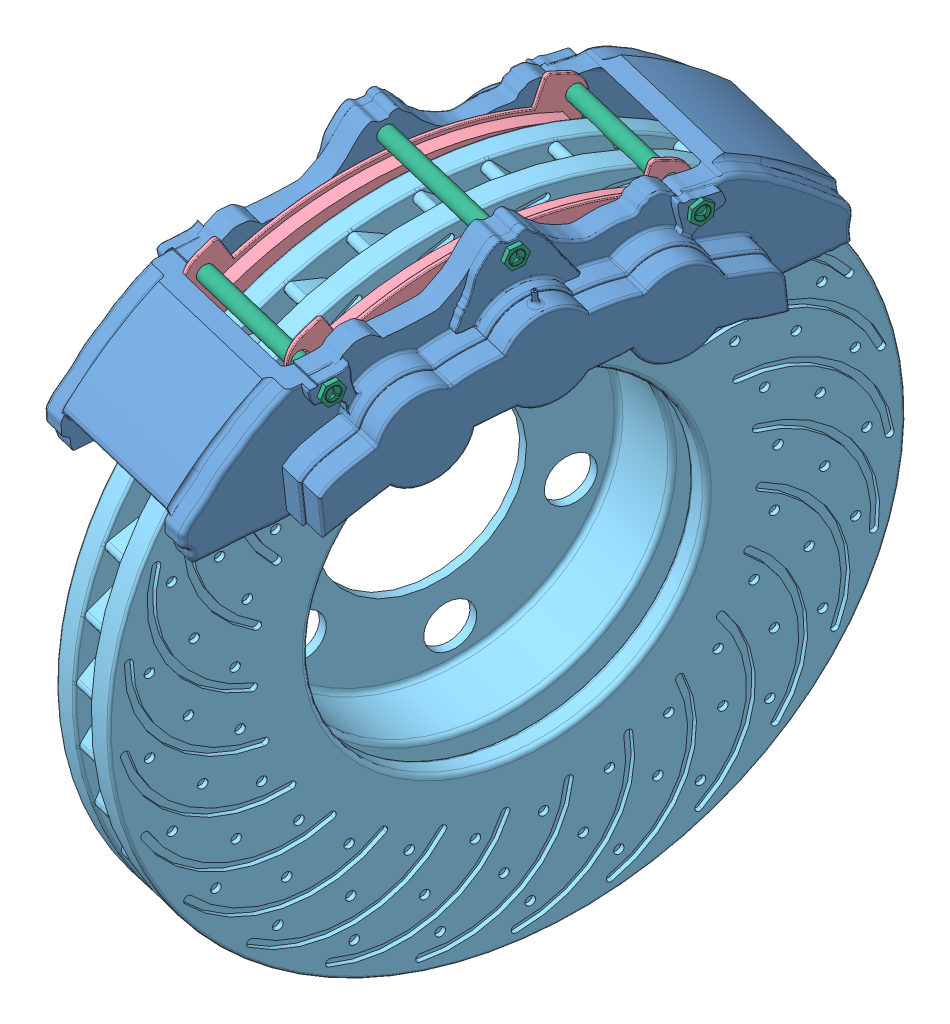
SolidWorks assembly Brake Assemble, configuration Default. Lengths in mm.
Overall size (85.72 212.78 212.98).
9 component instances, 6 part files, 19 mates.
Components (placement in the parent):
- Brake Caliper 1-1: Brake Caliper 1 [Default] at (-2.2395 31.9468 202.1188) x (0.977716 -0.038754 0.206322) z (-0.209533 -0.119701 0.970447) size (56.21 39.49 128.47)
- Brake piston (R)-1: Brake piston (R) [Default] at (36.2171 93.3172 217.992) x (0.208982 0.272999 -0.939041) z (0.019934 -0.961233 -0.275014) size (10 15 10)
- Piston rubber-1: Piston rubber [Default] at (45.9845 92.9301 220.0531) x (0.195813 0.52267 -0.829743) z (-0.075683 0.851654 0.518612) size (12.43 7.98 12.43)
- Brake Pad-1: Brake Pad [Default] at (8.2987 34.9481 206.059) x (0.977716 -0.038754 0.206322) z (0.048348 -0.914826 -0.400944) size (4.02 74.2 43.13)
- Brake Pad-2: Brake Pad [Default] at (34.2749 34.3435 211.2716) x (-0.977716 0.038754 -0.206322) z (-0.075256 -0.982195 0.172134) size (4.02 74.2 43.13)
- Rotor Brake -1: Rotor Brake  [Default] at (29.0837 32.7757 207.7171) x (-0.977716 0.038754 -0.206322) z (-0.110788 0.739558 0.663912) size (27 150 150)
- Sliding Pin-5: Sliding Pin [Default] at (51.7846 103.9726 187.4377) x (-0.977716 0.038754 -0.206322) z (-0.057387 -0.994718 0.085103) size (46.59 4.33 5)
- Sliding Pin-6: Sliding Pin [Default] at (44.7399 109.0172 221.7687) x (-0.977716 0.038754 -0.206322) z (0.092227 -0.803596 -0.587986) size (46.59 4.33 5)
- Sliding Pin-7: Sliding Pin [Default] at (37.1518 95.6132 255.2094) x (-0.977716 0.038754 -0.206322) z (0.092227 -0.803596 -0.587986) size (46.59 4.33 5)
Mates (geometry in assembly coordinates):
- Concentric3: concentric: cylinder of Brake Caliper 1-1 through (50.8829 92.7359 221.0868) axis (-0.977716 0.038754 -0.206322) radius 6.25; cylinder of Brake piston (R)-1 through (36.2171 93.3172 217.992) axis (-0.977716 0.038754 -0.206322) radius 4.5
- Concentric4: concentric: cylinder of Brake piston (R)-1 through (36.2171 93.3172 217.992) axis (-0.977716 0.038754 -0.206322) radius 4.5; cylinder of Piston rubber-1 through (38.1823 93.2393 218.4067) axis (0.977716 -0.038754 0.206322) radius 4.515
- Width1: width: plane of Brake piston (R)-1 through (44.9494 91.5647 224.7504) normal (-0.977716 0.038754 -0.206322); plane of Brake piston (R)-1 through (37.2321 92.0112 222.6303) normal (0.977716 -0.038754 0.206322); plane of Piston rubber-1 through (45.9845 92.9301 220.0531) normal (0.977716 -0.038754 0.206322); plane of Piston rubber-1 through (38.1823 93.2393 218.4067) normal (-0.977716 0.038754 -0.206322)
- Coincident4: coincident: plane of Brake piston (R)-1 through (35.1722 91.9522 222.6872) normal (-0.977716 0.038754 -0.206322); plane of Brake Pad-2 through (35.3498 35.8371 211.3052) normal (0.977716 -0.038754 0.206322)
- Width2: width: plane of Rotor Brake -1 through (14.4179 33.357 204.6223) normal (-0.977716 0.038754 -0.206322); plane of Rotor Brake -1 through (29.0837 32.7757 207.7171) normal (0.977716 -0.038754 0.206322); plane of Brake Pad-1 through (11.2318 34.8318 206.6779) normal (0.977716 -0.038754 0.206322); plane of Brake Pad-2 through (31.3418 34.4598 210.6526) normal (-0.977716 0.038754 -0.206322)
- Width3: width: plane of Brake Pad-1 through (11.2318 34.8318 206.6779) normal (0.977716 -0.038754 0.206322); plane of Brake Pad-2 through (31.3418 34.4598 210.6526) normal (-0.977716 0.038754 -0.206322); plane of Rotor Brake -1 through (29.0837 32.7757 207.7171) normal (0.977716 -0.038754 0.206322); plane of Rotor Brake -1 through (14.4179 33.357 204.6223) normal (-0.977716 0.038754 -0.206322)
- Distance5: distance = 3 mm: cylinder of Rotor Brake -1 through (4.6408 33.7445 202.5591) axis (0.977716 -0.038754 0.206322) radius 40; cylinder of Brake Pad-1 through (7.321 34.9869 205.8527) axis (0.977716 -0.038754 0.206322) radius 46.5
- Distance6: distance = 3 mm: cylinder of Brake Pad-2 through (35.2526 34.3048 211.4779) axis (-0.977716 0.038754 -0.206322) radius 46.5; cylinder of Rotor Brake -1 through (4.6408 33.7445 202.5591) axis (0.977716 -0.038754 0.206322) radius 40
- Coincident8: coincident: plane of Brake Caliper 1-1 through (20.3318 98.0959 156.051) normal (0.977716 -0.038754 0.206322); plane of Brake Pad-1 through (7.2661 36.4363 206.385) normal (-0.977716 0.038754 -0.206322)
- Concentric5: concentric: cylinder of Brake Caliper 1-1 through (60.3482 103.6332 189.2449) axis (-0.977716 0.038754 -0.206322) radius 1.75; cylinder of Sliding Pin-5 through (7.7874 105.7166 178.1532) axis (0.977716 -0.038754 0.206322) radius 1.75
- Coincident9: coincident: plane of Brake Caliper 1-1 through (52.1533 106.232 186.115) normal (0.977716 -0.038754 0.206322); plane of Sliding Pin-5 through (51.7846 103.9726 187.4377) normal (-0.977716 0.038754 -0.206322)
- Concentric6: concentric: cylinder of Brake Caliper 1-1 through (53.3035 108.6778 223.5758) axis (-0.977716 0.038754 -0.206322) radius 1.75; cylinder of Sliding Pin-6 through (0.7427 110.7611 212.4842) axis (0.977716 -0.038754 0.206322) radius 1.75
- Coincident10: coincident: plane of Brake Caliper 1-1 through (42.8419 103.6191 229.749) normal (0.977716 -0.038754 0.206322); plane of Sliding Pin-6 through (44.7399 109.0172 221.7687) normal (-0.977716 0.038754 -0.206322)
- Concentric7: concentric: cylinder of Brake Pad-2 through (33.6933 104.6897 183.62) axis (0.977716 -0.038754 0.206322) radius 1.75; cylinder of Sliding Pin-5 through (7.7874 105.7166 178.1532) axis (0.977716 -0.038754 0.206322) radius 1.75
- Concentric8: concentric: cylinder of Brake Pad-1 through (25.3863 105.019 181.867) axis (-0.977716 0.038754 -0.206322) radius 1.75; cylinder of Sliding Pin-5 through (7.7874 105.7166 178.1532) axis (0.977716 -0.038754 0.206322) radius 1.75
- Concentric9: concentric: cylinder of Brake Pad-1 through (10.7535 96.6596 249.6388) axis (-0.977716 0.038754 -0.206322) radius 1.75; cylinder of Sliding Pin-7 through (-6.8454 97.3572 245.925) axis (0.977716 -0.038754 0.206322) radius 1.75
- Coincident11: coincident: plane of Brake Caliper 1-1 through (36.5677 97.6867 258.3669) normal (0.977716 -0.038754 0.206322); plane of Sliding Pin-7 through (37.1518 95.6132 255.2094) normal (-0.977716 0.038754 -0.206322)
- Concentric10: concentric: cylinder of Brake Caliper 1-1 through (45.7154 95.2738 257.0166) axis (-0.977716 0.038754 -0.206322) radius 1.75; cylinder of Sliding Pin-7 through (-6.8454 97.3572 245.925) axis (0.977716 -0.038754 0.206322) radius 1.75
- Coincident13: coincident: plane of Brake Caliper 1-1 through (50.8829 92.7359 221.0868) normal (-0.977716 0.038754 -0.206322); plane of Brake piston (R)-1 through (50.8829 92.7359 221.0868) normal (0.977716 -0.038754 0.206322)
